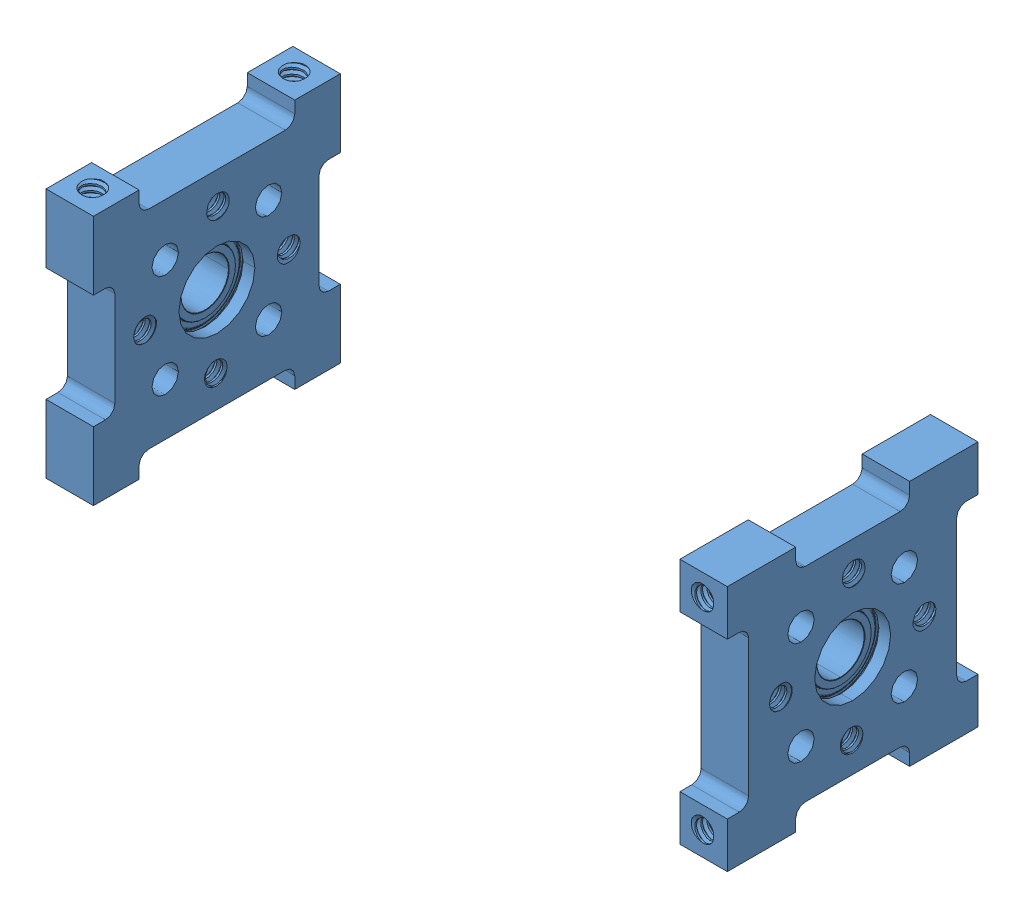
SolidWorks assembly ARMUS-REV4-400, configuration Défaut. Lengths in mm.
Overall size (128.27 130.43 130.79).
3 component instances, 2 part files, 8 mates.
Components (placement in the parent):
- ARMUS-REV4-401-1: ARMUS-REV4-401 [Default] at origin size (121.92 130.43 130.79)
- Bore Side Tapped Pillow Block 1.25-1: Bore Side Tapped Pillow Block 1.25 [Default] at (-58.9626 7.6184 28.3917) x (0 -1 0) z (0 0 -1) size (33.54 6.35 33.02)
- Bore Side Tapped Pillow Block 1.25-2: Bore Side Tapped Pillow Block 1.25 [Default] at (26.0822 -28.3917 7.6184) x (0 0 -1) z (0 1 0) size (33.54 6.35 33.02)
Mates (geometry in assembly coordinates):
- Concentric294: concentric anti-aligned: cylinder of ARMUS-REV4-401-1 through (128.2701 0 0) axis (-1 0 0) radius 6.35; cylinder of Bore Side Tapped Pillow Block 1.25-2 through (5.5295 0 0) axis (1 0 0) radius 3.175
- Concentric296: concentric anti-aligned: cylinder of ARMUS-REV4-401-1 through (5.5168 -6.9148 -6.9148) axis (1 0 0) radius 1.25; cylinder of Bore Side Tapped Pillow Block 1.25-2 through (5.5168 -6.9148 -6.9148) axis (-1 0 0) radius 1.778
- Concentric297: concentric anti-aligned: cylinder of ARMUS-REV4-401-1 through (5.5168 6.9148 -6.9148) axis (1 0 0) radius 1.25; cylinder of Bore Side Tapped Pillow Block 1.25-2 through (5.5168 6.9148 -6.9148) axis (-1 0 0) radius 1.778
- Coincident59: coincident anti-aligned: plane of ARMUS-REV4-401-1 through (5.5168 0 0) normal (1 0 0); plane of Bore Side Tapped Pillow Block 1.25-2 through (5.5168 0 0) normal (-1 0 0)
- Coincident60: coordinate: point of ARMUS-REV4-401-1
- Concentric299: concentric anti-aligned: cylinder of ARMUS-REV4-401-1 through (5.5168 -6.9148 -6.9148) axis (1 0 0) radius 1.25; cylinder of Bore Side Tapped Pillow Block 1.25-1 through (-79.5281 -6.9148 -6.9148) axis (-1 0 0) radius 1.778
- Coincident61: coincident anti-aligned: plane of ARMUS-REV4-401-1 through (-73.1781 -65.2174 -19.05) normal (-1 0 0); plane of Bore Side Tapped Pillow Block 1.25-1 through (-73.1781 0 0) normal (1 0 0)
- Concentric301: concentric anti-aligned: cylinder of ARMUS-REV4-401-1 through (5.5168 6.9148 6.9148) axis (1 0 0) radius 1.25; cylinder of Bore Side Tapped Pillow Block 1.25-1 through (-79.5281 6.9148 6.9148) axis (-1 0 0) radius 1.778
